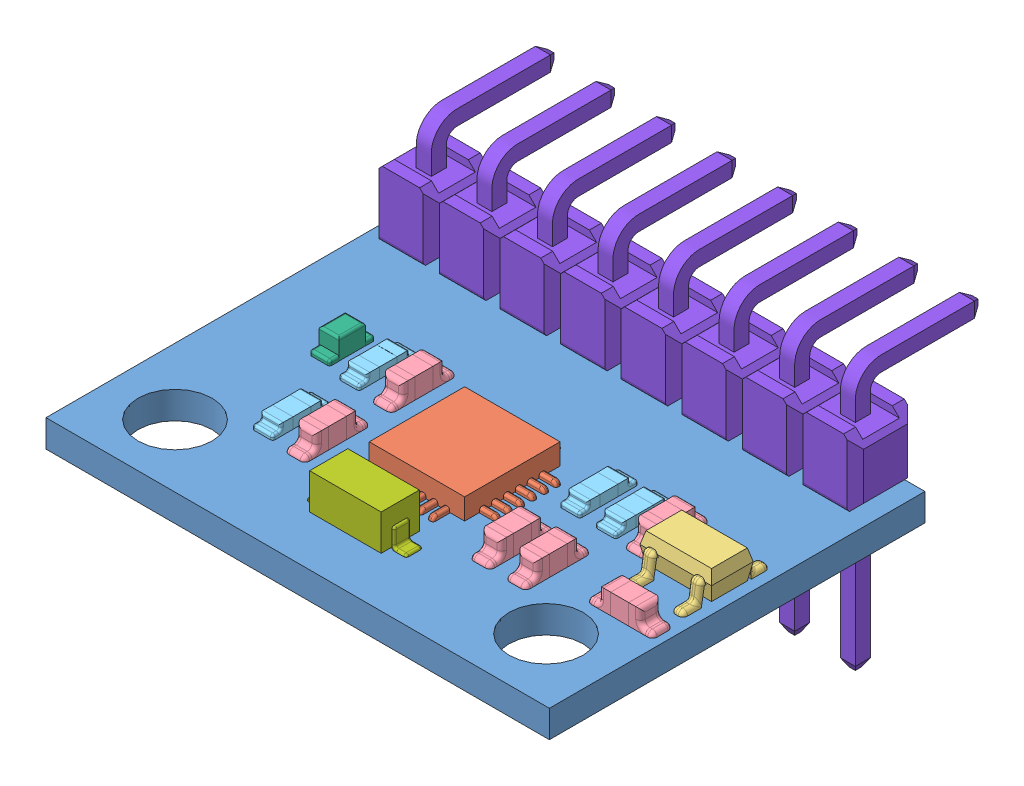
SolidWorks assembly MPU 6050 IMU, configuration Default. Lengths in mm.
Overall size (21.11 11.26 19.63).
16 component instances, 8 part files, 33 mates.
Components (placement in the parent):
- Base-1: Base [Default] at (7.2489 10.9584 16.5726) size (21.11 1.14 15.75)
- sensor chip-1: sensor chip [Default] at (7.2489 11.5499 17.4466) size (5.4 0.9 5.4)
- S2NH chip-1: S2NH chip [Default] at (16.1026 12.3799 16.5726) size (3 1.35 3.65)
- Resistor small-3: Resistor small [Default] at (16.1026 11.5314 19.3726) size (2.75 0.99 1)
- Resistor small-4: Resistor small [Default] at (13.9776 11.5314 15.6976) x (0 0 -1) z (1 0 0) size (2.75 0.99 1)
- Resistor small black-3: Resistor small black [Default] at (12.6276 11.5299 15.6976) x (0 0 1) z (-1 0 0) size (2.45 0.6 1.02)
- Resistor small black-4: Resistor small black [Default] at (11.1276 11.5299 15.6976) x (0 0 1) z (-1 0 0) size (2.45 0.6 1.02)
- Resistor small-5: Resistor small [Default] at (12.6276 11.5314 19.3216) x (0 0 -1) z (1 0 0) size (2.75 0.99 1)
- Resistor small-6: Resistor small [Default] at (11.1276 11.5314 19.3216) x (0 0 -1) z (1 0 0) size (2.75 0.99 1)
- Resistor small-7: Resistor small [Default] at (3.3702 11.5314 19.3216) x (0 0 -1) z (1 0 0) size (2.75 0.99 1)
- Resistor small black-5: Resistor small black [Default] at (1.8702 11.5299 15.6972) x (0 0 -1) z (1 0 0) size (2.45 0.6 1.02)
- Resistor small-8: Resistor small [Default] at (3.3702 11.5314 15.6976) x (0 0 1) z (-1 0 0) size (2.75 0.99 1)
- Small LED-1: Small LED [Default] at (0.3652 11.5299 15.6976) size (0.85 0.84 1.9)
- Resistor small black-6: Resistor small black [Default] at (1.8702 11.5299 19.3216) x (0 0 1) z (-1 0 0) size (2.45 0.6 1.02)
- Resistor black-1: Resistor black [Default] at (7.2489 12.3799 21.6466) size (4.2 1.6 1.6)
- Pin Header 1x8 TH Angle Pitch 2.54mm.stp-1: Pin Header 1x8 TH Angle Pitch 2.54mm.stp [Default] at (-1.7551 15.6761 8.0216) x (0.999997 -0.0026 0) z (0 0 1) size (20.33 11.2 6.3)
Mates (geometry in assembly coordinates):
- Coincident6: coincident: plane of Base-1 through (7.2489 11.5299 16.5726) normal (0 1 0); plane of sensor chip-1 through (7.2489 11.5299 17.4466) normal (0 -1 0)
- Coincident7: coincident: plane of Base-1 through (7.2489 10.9584 16.5726) normal (1 0 0); plane of sensor chip-1 through (7.2489 11.5499 17.4466) normal (1 0 0)
- Distance1: distance = 5 mm: plane of sensor chip-1 through (5.2489 12.4299 19.4466) normal (0 0 1); plane of Base-1 through (-3.3048 11.5299 24.4466) normal (0 0 1)
- Coincident8: coincident: plane of Base-1 through (7.2489 11.5299 16.5726) normal (0 1 0); plane of S2NH chip-1 through (16.1026 11.5299 16.5726) normal (0 -1 0)
- Coincident9: coincident: plane of Base-1 through (7.2489 10.9584 16.5726) normal (0 0 1); plane of S2NH chip-1 through (16.1026 12.3799 16.5726) normal (0 0 1)
- Distance2: distance = 0.2 mm: line of S2NH chip-1 through (17.6026 12.3799 17.4476) axis (0 0 -1); plane of Base-1 through (17.8026 11.5299 24.4466) normal (1 0 0)
- Coincident19: coincident: plane of Base-1 through (7.2489 11.5299 16.5726) normal (0 1 0); plane of Resistor small-3 through (16.9776 11.5299 19.8026) normal (0 -1 0)
- Coincident20: coincident: plane of S2NH chip-1 through (16.1026 12.3799 16.5726) normal (1 0 0); plane of Resistor small-3 through (16.1026 11.5314 19.3726) normal (1 0 0)
- Distance5: distance = 1.5 mm: line of S2NH chip-1 through (15.3258 12.3799 17.4476) axis (1 0 0); plane of Resistor small-3 through (16.4776 11.5314 18.9476) normal (0 0 -1)
- Coincident22: coincident: plane of Base-1 through (7.2489 11.5299 16.5726) normal (0 1 0); plane of Resistor small-4 through (14.4076 11.5299 14.8226) normal (0 -1 0)
- Coincident24: coincident: line of S2NH chip-1 through (16.8794 12.3799 15.6976) axis (-1 0 0); plane of Resistor small-4 through (13.9776 11.5314 15.6976) normal (0 0 -1)
- Distance6: distance = 0.2 mm: plane of Resistor small-4 through (14.4026 11.5314 15.3226) normal (1 0 0); line of S2NH chip-1 through (14.6026 12.3799 15.6976) axis (0 0 1)
- Coincident26: coincident: plane of Base-1 through (7.2489 11.5299 16.5726) normal (0 1 0); plane of Resistor small black-3 through (12.2026 11.5299 16.0726) normal (0 -1 0)
- Coincident28: coincident: plane of Resistor small-4 through (13.9776 11.5314 15.6976) normal (0 0 -1); plane of Resistor small black-3 through (12.6276 11.5299 15.6976) normal (0 0 1)
- Distance7: distance = 0.5 mm: plane of Resistor small-4 through (13.5526 11.5314 15.3226) normal (-1 0 0); plane of Resistor small black-3 through (13.0526 11.5299 16.0726) normal (1 0 0)
- Coincident30: coincident: plane of Base-1 through (7.2489 11.5299 16.5726) normal (0 1 0); plane of Resistor small-5 through (13.0576 11.5299 18.4466) normal (0 -1 0)
- Coincident31: coincident: plane of Resistor small black-3 through (12.6276 11.5299 15.6976) normal (-1 0 0); plane of Resistor small-5 through (12.6276 11.5314 19.3216) normal (1 0 0)
- Distance8: distance = 4.25 mm: plane of Resistor small-5 through (12.6276 11.5314 20.1966) normal (0 0 1); plane of Base-1 through (-3.3048 11.5299 24.4466) normal (0 0 1)
- Coincident33: coincident: plane of Base-1 through (7.2489 11.5299 16.5726) normal (0 1 0); plane of Resistor small-8 through (2.9402 11.5299 14.8226) normal (0 -1 0)
- Coincident34: coincident: plane of Resistor small-7 through (3.3702 11.5314 19.3216) normal (1 0 0); plane of Resistor small-8 through (3.3702 11.5314 15.6976) normal (-1 0 0)
- Coincident36: coincident: line of S2NH chip-1 through (15.8794 12.3799 15.6976) axis (-1 0 0); plane of Resistor small-8 through (3.3702 11.5314 15.6976) normal (0 0 1)
- Coincident37: coincident: plane of Base-1 through (7.2489 11.5299 16.5726) normal (0 1 0); plane of Small LED-1 through (0.3652 11.5299 15.6976) normal (0 -1 0)
- Coincident38: coincident: line of S2NH chip-1 through (15.8794 12.3799 15.6976) axis (-1 0 0); plane of Small LED-1 through (0.3652 11.5299 15.6976) normal (0 0 1)
- Distance9: distance = 1.5 mm: plane of Small LED-1 through (-0.0548 12.3699 16.2476) normal (-1 0 0); plane of Resistor small black-5 through (1.4452 11.5299 15.3222) normal (-1 0 0)
- Coincident40: coincident: plane of Base-1 through (7.2489 11.5299 16.5726) normal (0 1 0); plane of Resistor small black-6 through (1.4452 11.5299 19.6966) normal (0 -1 0)
- Coincident41: coincident: plane of Resistor small black-5 through (1.8702 11.5299 15.6972) normal (1 0 0); plane of Resistor small black-6 through (1.8702 11.5299 19.3216) normal (-1 0 0)
- Coincident42: coincident: plane of Resistor small-7 through (3.3702 11.5314 19.3216) normal (0 0 -1); plane of Resistor small black-6 through (1.8702 11.5299 19.3216) normal (0 0 1)
- Coincident43: coincident: plane of Base-1 through (7.2489 11.5299 16.5726) normal (0 1 0); plane of Resistor black-1 through (5.6489 11.5299 21.9966) normal (0 -1 0)
- Coincident44: coincident: plane of Base-1 through (7.2489 10.9584 16.5726) normal (1 0 0); plane of Resistor black-1 through (7.2489 12.3799 21.6466) normal (1 0 0)
- Distance10: distance = 2 mm: plane of Resistor black-1 through (5.7489 13.1299 22.4466) normal (0 0 1); plane of Base-1 through (-3.3048 11.5299 24.4466) normal (0 0 1)
- Concentric4: concentric: circle of Pin Header 1x8 TH Angle Pitch 2.54mm.stp-1; circle of Base-1
- Coincident46: coincident: plane of Base-1 through (7.2489 11.5299 16.5726) normal (0 1 0); plane of Pin Header 1x8 TH Angle Pitch 2.54mm.stp-1 through (16.9678 11.5299 11.137) normal (0 -1 0)
- Concentric6: concentric: cylinder of Base-1 through (16.0246 11.5299 9.8416) axis (0 -1 0) radius 0.508; circle of Pin Header 1x8 TH Angle Pitch 2.54mm.stp-1
